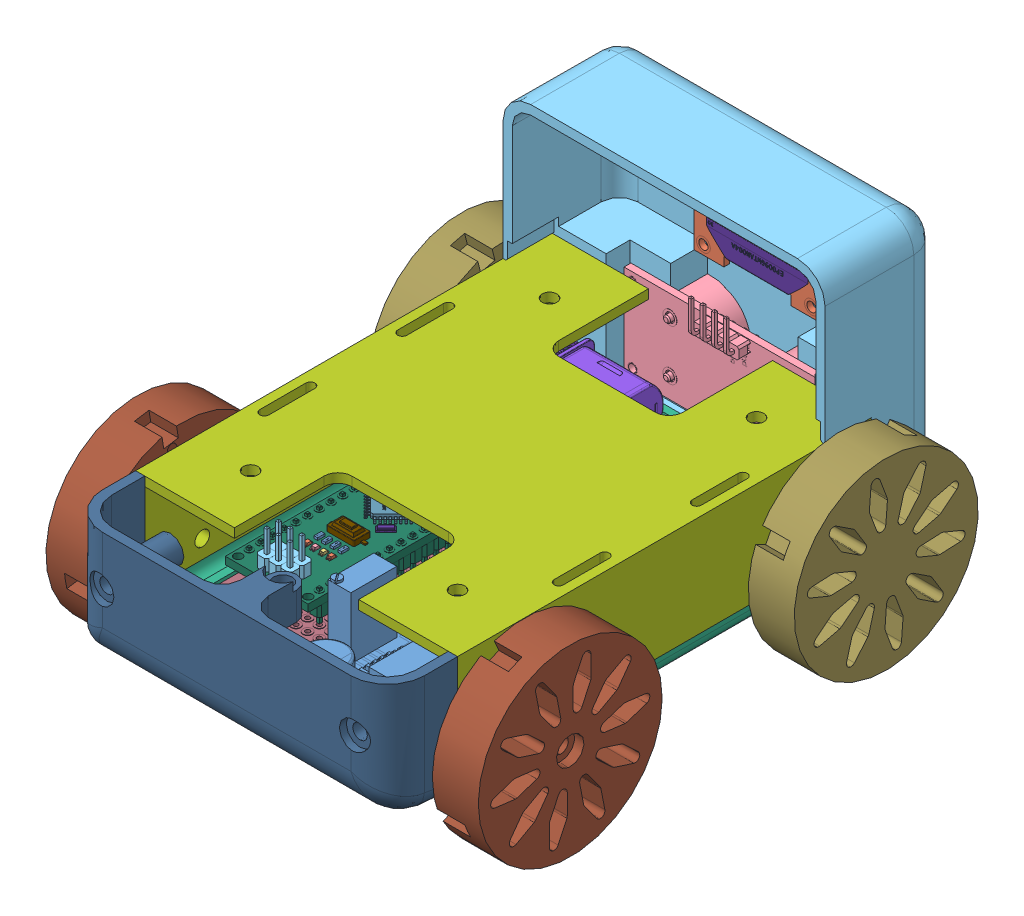
SolidWorks assembly assembling, configuration По умолчанию. Lengths in mm.
Overall size (94 77.03 124.24).
205 component instances, 165 part files, 54 mates.
Components (placement in the parent):
- Weewooday I2C OLED 0.98 128x64.step-2: Weewooday I2C OLED 0.98 128x64.step [По умолчанию] at (61.75 -43.4059 -15.8059) x (-1 0 0) z (0 1 0) size (27.5 4.33 27.8)
  - Weewooday I2C OLED 0.96'' 128x64.step-1: Weewooday I2C OLED 0.96'' 128x64.step [По умолчанию] at origin size (27.5 4.33 27.8)
    - bits.step-1: bits.step [По умолчанию] at origin size (25.27 1.31 10.1)
      - 662k - XC6206P182MR-G_1.step-1: 662k - XC6206P182MR-G_1.step [По умолчанию] at origin size (2.9 1.31 2.79)
      - R SMD 472_1.step-1: R SMD 472_1.step [По умолчанию] at origin size (0.89 0.56 1.7)
      - R SMD 472_2.step-1: R SMD 472_2.step [По умолчанию] at origin size (0.89 0.56 1.7)
      - R SMD 472_3.step-1: R SMD 472_3.step [По умолчанию] at origin size (0.89 0.56 1.7)
      - R SMD 914_1.step-1: R SMD 914_1.step [По умолчанию] at origin size (0.89 0.56 1.7)
      - R SMD 472_4.step-1: R SMD 472_4.step [По умолчанию] at origin size (1.7 0.56 0.89)
      - C SMD 0603_1.step-1: C SMD 0603_1.step [По умолчанию] at origin size (0.8 0.8 1.6)
      - C SMD 0603_2.step-1: C SMD 0603_2.step [По умолчанию] at origin size (0.8 0.8 1.6)
      - C SMD 0603_3.step-1: C SMD 0603_3.step [По умолчанию] at origin size (0.8 0.8 1.6)
      - C SMD 0603_4.step-1: C SMD 0603_4.step [По умолчанию] at origin size (0.8 0.8 1.6)
      - C SMD 0603_5.step-1: C SMD 0603_5.step [По умолчанию] at origin size (0.8 0.8 1.6)
      - C SMD 0603_6.step-1: C SMD 0603_6.step [По умолчанию] at origin size (0.8 0.8 1.6)
      - C SMD 0603_7.step-1: C SMD 0603_7.step [По умолчанию] at origin size (0.8 0.8 1.6)
      - C SMD 0603_8.step-1: C SMD 0603_8.step [По умолчанию] at origin size (0.8 0.8 1.6)
      - SOD323F_DIO_1.step-1: SOD323F_DIO_1.step [По умолчанию] at origin size (0.75 0.82 2.5)
    - flat_cable_1.step-1: flat_cable_1.step [По умолчанию] at origin size (22.01 3.08 9.32)
      - pins.step-1: pins.step [По умолчанию] at origin size (21.2 0.05 3)
      - flat_cable_1-0.step-1: flat_cable_1-0.step [По умолчанию] at origin size (22.01 3.08 7.82)
    - pads.step-1: pads.step [По умолчанию] at origin size (25.48 0.01 10.54)
    - silk screen.step-1: silk screen.step [По умолчанию] at origin size (27.48 1.25 23.58)
    - board_1.step-1: board_1.step [По умолчанию] at origin size (27.5 1.23 27.8)
    - screen_1.step-1: screen_1.step [По умолчанию] at origin size (26.7 1.8 19.26)
- Ultrasonic sensor.step-2: Ultrasonic sensor.step [По умолчанию] at (-26.4481 -23.7121 67.4064) x (-1 0 0) z (0 1 0) size (45 17.8 25.83)
  - ultrasonic sensor.step-1: ultrasonic sensor.step [По умолчанию] at (-40.1981 -57.9064 -18.4379) x (-1 0 0) z (0 -1 0) size (45 25.83 17.8)
- front-bumper-2: front-bumper [По умолчанию] at (13.75 -26.9 -2) x (-1 0 0) z (0 1 0) size (70.34 25.3 58.17)
- bottom-2: bottom [По умолчанию] at (13.75 -55.9 58.2) size (70 10 90)
- User Library-R6_AA_UM3-1_5V_holder4AA(1)-2: User Library-R6_AA_UM3-1_5V_holder4AA(1) [4AA] at (13.75 -14.813 58.2) x (0 0 1) z (0 -1 0) size (59.56 61.47 30.23) (hidden)
- base-2: base [По умолчанию] at (13.75 -51.9 58.2) x (0 0 1) z (0 1 0) size (90 74 22)
- N20 Mini Micro Metall Gear Motor DC 3-6-12V v1-3: N20 Mini Micro Metall Gear Motor DC 3-6-12V v1 [По умолчанию] at (36.95 -47.9 21.2) x (1 0 0) z (0 1 0) size (34.2 12.11 10.34)
- N20 Mini Micro Metall Gear Motor DC 3-6-12V v1-4: N20 Mini Micro Metall Gear Motor DC 3-6-12V v1 [По умолчанию] at (-9.45 -47.9 21.2) x (-1 0 0) z (0 1 0) size (34.2 12.11 10.34)
- 693 ZZ 3-8-4-3: 693 ZZ 3-8-4 [По умолчанию] at (-24.75 -47.9 90.7) x (0 0.003804 0.999993) z (-1 0 0) size (8 8 4)
- 693 ZZ 3-8-4-4: 693 ZZ 3-8-4 [По умолчанию] at (53.25 -47.9 90.7) x (0 0.003804 0.999993) z (-1 0 0) size (8 8 4)
- back-bumper-2: back-bumper [По умолчанию] at (13.75 -29.8 118.4) x (1 0 0) z (0 1 0) size (70.34 15.21 26.17)
- roof-2: roof [По умолчанию] at (13.75 2.1 70.85) x (1 0 0) z (0 0 -1) size (70 34 99.1) (hidden)
- back-wheel-1: back-wheel [По умолчанию] at (-33.25 -47.9 90.7) x (0 -0.987279 -0.158998) z (0 -0.158998 0.987279) size (40 10 40)
- back-wheel-2: back-wheel [По умолчанию] at (60.75 -47.9 90.7) x (0 -0.916751 -0.399458) z (0 0.399458 -0.916751) size (40 10 40)
- front-wheel-1: front-wheel [По умолчанию] at (59.95 -47.9 21.2) x (0 0.883956 -0.46757) z (0 0.46757 0.883956) size (40 10 40)
- front-wheel-2: front-wheel [По умолчанию] at (-32.45 -47.9 21.2) x (0 0.97042 0.241423) z (0 0.241423 -0.97042) size (40 10 40)
- pcb_5x7.step-1: pcb_5x7.step [По умолчанию] at (13.75 -50.3 65.2342) x (0 0 1) z (0 1 0) size (70 50 1.8)
- Arduino Nano.step-1: Arduino Nano.step [По умолчанию] at (-17.2484 -45.3384 50.0291) x (0 0 1) z (0 1 0) size (44.28 18 13.68)
  - ATMEGA328P-AU.STEP.step-1: ATMEGA328P-AU.STEP.step [По умолчанию] at (19.8219 24.4243 4.0882) x (-0.707107 -0.707107 0) z (0 0 1) size (9 9 1.2)
    - ATMEGA328P-AU--3DModel-STEP-56544.step.STEP.STEP.STEP.step-1: ATMEGA328P-AU--3DModel-STEP-56544.step.STEP.STEP.STEP.step [По умолчанию] at (2.8163 4.1 0.6768) x (1 0 0) z (0 -1 0) size (9 1.2 9)
  - Arduino Nano_1.step-1: Arduino Nano_1.step [По умолчанию] at (8.8551 11.9484 0) size (43.18 18 6.8)
  - Mini USB.step-1: Mini USB.step [По умолчанию] at (8.5451 19.5727 4.14) size (9.5 9.7 3.9)
  - CSTCE Crystal.step-1: CSTCE Crystal.step [По умолчанию] at (25.8562 23.1047 4.15) x (0.707107 -0.707107 0) z (0 0 1) size (3.2 1.35 0.71)
  - 2Pin Tactile Switch 6x3.6.step-1: 2Pin Tactile Switch 6x3.6.step [По умолчанию] at (30.7142 19.8184 4.14) x (0 1 0) z (0 0 1) size (7.9 3.6 2.2)
  - 0603 Resistor.step-1: 0603 Resistor.step [По умолчанию] at (34.4251 22.4184 4.14) size (1.6 0.8 0.5)
  - 0603 Resistor.step-2: 0603 Resistor.step [По умолчанию] at (34.4251 20.7184 4.14) size (1.6 0.8 0.5)
  - 0603 Resistor.step-3: 0603 Resistor.step [По умолчанию] at (34.4251 18.9184 4.14) size (1.6 0.8 0.5)
  - 0603 Resistor.step-4: 0603 Resistor.step [По умолчанию] at (34.4251 17.2184 4.14) size (1.6 0.8 0.5)
  - Blue LED.step-1: Blue LED.step [По умолчанию] at (37.0251 22.4184 4.14) size (1.6 0.8 0.6)
  - Green LED.step-1: Green LED.step [По умолчанию] at (37.0251 20.7184 4.14) size (1.6 0.8 0.6)
  - Red LED.step-1: Red LED.step [По умолчанию] at (37.0251 18.9184 4.14) size (1.6 0.8 0.6)
  - Blue LED.step-2: Blue LED.step [По умолчанию] at (37.0251 17.2184 4.14) size (1.6 0.8 0.6)
  - Header 2x3.step-1: Header 2x3.step [По умолчанию] at (45.6765 17.0321 4.14) x (0 1 0) z (0 0 1) size (7.62 5.07 10)
  - SOT89.step-1: SOT89.step [По умолчанию] at (38.4751 17.3184 0.94) x (0 1 0) z (0 0 1) size (6.5 7.1 1.6)
  - 1206 Tantalum.step-1: 1206 Tantalum.step [По умолчанию] at (38.6251 22.3684 2.54) x (-1 0 0) z (0 0 -1) size (3.2 1.6 1.5)
  - 0603 Resistor.step-5: 0603 Resistor.step [По умолчанию] at (38.4251 24.9684 2.54) x (-1 0 0) z (0 0 -1) size (1.6 0.8 0.5)
  - 0603 Capacitor.step-1: 0603 Capacitor.step [По умолчанию] at (35.0338 14.4684 2.54) x (-1 0 0) z (0 0 -1) size (1.6 0.8 0.7)
  - 1206 Tantalum.step-2: 1206 Tantalum.step [По умолчанию] at (7.6451 24.3684 2.54) x (1 0 0) z (0 0 -1) size (3.2 1.6 1.5)
  - 0603 Capacitor.step-2: 0603 Capacitor.step [По умолчанию] at (6.9059 22.4745 2.54) x (-1 0 0) z (0 0 -1) size (1.6 0.8 0.7)
  - 0603 Capacitor.step-3: 0603 Capacitor.step [По умолчанию] at (17.8451 14.0245 2.54) x (-1 0 0) z (0 0 -1) size (1.6 0.8 0.7)
  - 0603 Capacitor.step-4: 0603 Capacitor.step [По умолчанию] at (17.8451 15.0767 2.54) x (-1 0 0) z (0 0 -1) size (1.6 0.8 0.7)
  - 0603 Capacitor.step-5: 0603 Capacitor.step [По умолчанию] at (25.3451 21.2855 2.54) x (-1 0 0) z (0 0 -1) size (1.6 0.8 0.7)
  - 0603 Resistor.step-6: 0603 Resistor.step [По умолчанию] at (23.8451 15.8601 2.54) x (-1 0 0) z (0 0 -1) size (1.6 0.8 0.5)
  - 0603 Resistor.step-7: 0603 Resistor.step [По умолчанию] at (23.8451 14.4709 2.54) x (-1 0 0) z (0 0 -1) size (1.6 0.8 0.5)
  - CSTCE Crystal.step-2: CSTCE Crystal.step [По умолчанию] at (13.1731 14.7184 2.53) x (-1 0 0) z (0 0 -1) size (3.2 1.35 0.71)
  - SOIC16.step-1: SOIC16.step [По умолчанию] at (16.6451 19.5642 2.54) x (-1 0 0) z (0 0 -1) size (10.2 6 1.5)
- Sparkfun Motor Driver.step-1: Sparkfun Motor Driver.step [По умолчанию] at (26.5355 -43.7326 33.0099) x (0 0 -1) z (0 1 0) size (20.9 20.98 11.14)
  - pin6.step-1: pin6.step [По умолчанию] at (-6.347 18.1939 -12.4725) x (1 0 0) z (0 -1 0) size (2.45 11.14 2.54)
  - pin6.step-2: pin6.step [По умолчанию] at (-6.347 15.6539 -12.4725) x (1 0 0) z (0 -1 0) size (2.45 11.14 2.54)
  - pin6.step-3: pin6.step [По умолчанию] at (-6.347 13.1139 -12.4725) x (1 0 0) z (0 -1 0) size (2.45 11.14 2.54)
  - pin6.step-4: pin6.step [По умолчанию] at (-6.347 10.5739 -12.4725) x (1 0 0) z (0 -1 0) size (2.45 11.14 2.54)
  - pin6.step-5: pin6.step [По умолчанию] at (-6.347 8.0339 -12.4725) x (1 0 0) z (0 -1 0) size (2.45 11.14 2.54)
  - pin6.step-6: pin6.step [По умолчанию] at (-6.347 5.4939 -12.4725) x (1 0 0) z (0 -1 0) size (2.45 11.14 2.54)
  - pin6.step-7: pin6.step [По умолчанию] at (-6.347 2.9539 -12.4725) x (1 0 0) z (0 -1 0) size (2.45 11.14 2.54)
  - pin6.step-8: pin6.step [По умолчанию] at (-6.347 0.4139 -12.4725) x (1 0 0) z (0 -1 0) size (2.45 11.14 2.54)
  - pin6.step-9: pin6.step [По умолчанию] at (-21.333 0.4139 -12.4725) x (1 0 0) z (0 -1 0) size (2.45 11.14 2.54)
  - pin6.step-10: pin6.step [По умолчанию] at (-21.333 2.9539 -12.4725) x (1 0 0) z (0 -1 0) size (2.45 11.14 2.54)
  - pin6.step-11: pin6.step [По умолчанию] at (-21.333 5.4939 -12.4725) x (1 0 0) z (0 -1 0) size (2.45 11.14 2.54)
  - pin6.step-12: pin6.step [По умолчанию] at (-21.333 8.0339 -12.4725) x (1 0 0) z (0 -1 0) size (2.45 11.14 2.54)
  - pin6.step-13: pin6.step [По умолчанию] at (-21.333 10.5739 -12.4725) x (1 0 0) z (0 -1 0) size (2.45 11.14 2.54)
  - pin6.step-14: pin6.step [По умолчанию] at (-21.333 13.1139 -12.4725) x (1 0 0) z (0 -1 0) size (2.45 11.14 2.54)
  - pin6.step-15: pin6.step [По умолчанию] at (-21.333 15.6539 -12.4725) x (1 0 0) z (0 -1 0) size (2.45 11.14 2.54)
  - pin6.step-16: pin6.step [По умолчанию] at (-21.333 18.1939 -12.4725) x (1 0 0) z (0 -1 0) size (2.45 11.14 2.54)
  - Motor Driver.step-1: Motor Driver.step [По умолчанию] at origin size (20.9 20.98 1.65)
  - Motor Driver-0.step-1: Motor Driver-0.step [По умолчанию] at origin size (0.63 0.64 0.01)
  - Motor Driver-1.step-1: Motor Driver-1.step [По умолчанию] at origin size (2.01 3.8 0.01)
  - Motor Driver-2.step-1: Motor Driver-2.step [По умолчанию] at origin size (3.81 1.83 0.03)
  - Motor Driver-3.step-1: Motor Driver-3.step [По умолчанию] at origin size (1.81 3.8 0.01)
  - Motor Driver-4.step-1: Motor Driver-4.step [По умолчанию] at origin size (3.81 1.83 0.03)
  - Motor Driver-5.step-1: Motor Driver-5.step [По умолчанию] at origin size (3.81 1.83 0.03)
  - Motor Driver-6.step-1: Motor Driver-6.step [По умолчанию] at origin size (3.81 1.83 0.03)
  - Motor Driver-7.step-1: Motor Driver-7.step [По умолчанию] at origin size (3.81 1.83 0.03)
  - Motor Driver-8.step-1: Motor Driver-8.step [По умолчанию] at origin size (3.81 1.83 0.03)
  - Motor Driver-9.step-1: Motor Driver-9.step [По умолчанию] at origin size (3.81 1.83 0.03)
  - Motor Driver-10.step-1: Motor Driver-10.step [По умолчанию] at origin size (3.81 1.83 0.03)
  - Motor Driver-11.step-1: Motor Driver-11.step [По умолчанию] at origin size (3.81 1.83 0.03)
  - Motor Driver-12.step-1: Motor Driver-12.step [По умолчанию] at origin size (3.81 1.83 0.03)
  - Motor Driver-13.step-1: Motor Driver-13.step [По умолчанию] at origin size (3.81 1.83 0.03)
  - Motor Driver-14.step-1: Motor Driver-14.step [По умолчанию] at origin size (3.81 1.83 0.03)
  - Motor Driver-15.step-1: Motor Driver-15.step [По умолчанию] at origin size (3.81 1.83 0.03)
  - Motor Driver-16.step-1: Motor Driver-16.step [По умолчанию] at origin size (3.81 1.83 0.03)
  - Motor Driver-17.step-1: Motor Driver-17.step [По умолчанию] at origin size (3.81 1.83 0.03)
  - Motor Driver-18.step-1: Motor Driver-18.step [По умолчанию] at origin size (3.81 1.83 0.03)
  - Motor Driver-19.step-1: Motor Driver-19.step [По умолчанию] at origin size (1.8 0.86 0.64)
  - Motor Driver-20.step-1: Motor Driver-20.step [По умолчанию] at origin size (1.8 0.86 0.64)
  - Motor Driver-21.step-1: Motor Driver-21.step [По умолчанию] at origin size (4.17 2.79 1.92)
  - Motor Driver-22.step-1: Motor Driver-22.step [По умолчанию] at origin size (0.63 0.64 0.01)
  - Motor Driver-23.step-1: Motor Driver-23.step [По умолчанию] at origin size (1.27 0.91 0.66)
  - Motor Driver-24.step-1: Motor Driver-24.step [По умолчанию] at origin size (1.27 0.91 0.66)
  - Motor Driver-25.step-1: Motor Driver-25.step [По умолчанию] at origin size (5.03 6.97 1.14)
  - Motor Driver-26.step-1: Motor Driver-26.step [По умолчанию] at origin size (4.37 0.38 0.01)
  - Motor Driver-27.step-1: Motor Driver-27.step [По умолчанию] at origin size (4.37 0.38 0.01)
  - Motor Driver-28.step-1: Motor Driver-28.step [По умолчанию] at origin size (0.65 0.89 0.02)
  - Motor Driver-29.step-1: Motor Driver-29.step [По умолчанию] at origin size (0.84 0.89 0.02)
  - Motor Driver-30.step-1: Motor Driver-30.step [По умолчанию] at origin size (0.65 0.89 0.02)
  - Motor Driver-31.step-1: Motor Driver-31.step [По умолчанию] at origin size (0.73 0.92 0.02)
  - Motor Driver-32.step-1: Motor Driver-32.step [По умолчанию] at origin size (0.76 0.89 0.02)
  - Motor Driver-33.step-1: Motor Driver-33.step [По умолчанию] at origin size (0.52 0.89 0.02)
  - Motor Driver-34.step-1: Motor Driver-34.step [По умолчанию] at origin size (0.65 0.89 0.02)
  - Motor Driver-35.step-1: Motor Driver-35.step [По умолчанию] at origin size (0.66 0.89 0.02)
  - Motor Driver-36.step-1: Motor Driver-36.step [По умолчанию] at origin size (0.73 0.92 0.02)
  - Motor Driver-37.step-1: Motor Driver-37.step [По умолчанию] at origin size (0.39 0.89 0.02)
  - Motor Driver-38.step-1: Motor Driver-38.step [По умолчанию] at origin size (0.65 0.89 0.02)
  - Motor Driver-39.step-1: Motor Driver-39.step [По умолчанию] at origin size (1.49 0.27 0.85)
  - Motor Driver-40.step-1: Motor Driver-40.step [По умолчанию] at origin size (1.49 0.27 0.85)
  - Motor Driver-41.step-1: Motor Driver-41.step [По умолчанию] at origin size (1.49 0.27 0.85)
  - Motor Driver-42.step-1: Motor Driver-42.step [По умолчанию] at origin size (1.49 0.27 0.85)
  - Motor Driver-43.step-1: Motor Driver-43.step [По умолчанию] at origin size (1.49 0.27 0.85)
  - Motor Driver-44.step-1: Motor Driver-44.step [По умолчанию] at origin size (1.49 0.27 0.85)
  - Motor Driver-45.step-1: Motor Driver-45.step [По умолчанию] at origin size (1.49 0.27 0.85)
  - Motor Driver-46.step-1: Motor Driver-46.step [По умолчанию] at origin size (1.49 0.27 0.85)
  - Motor Driver-47.step-1: Motor Driver-47.step [По умолчанию] at origin size (1.49 0.27 0.85)
  - Motor Driver-48.step-1: Motor Driver-48.step [По умолчанию] at origin size (1.49 0.27 0.85)
  - Motor Driver-49.step-1: Motor Driver-49.step [По умолчанию] at origin size (1.49 0.27 0.85)
  - Motor Driver-50.step-1: Motor Driver-50.step [По умолчанию] at origin size (1.49 0.27 0.85)
  - Motor Driver-51.step-1: Motor Driver-51.step [По умолчанию] at origin size (1.49 0.27 0.85)
  - Motor Driver-52.step-1: Motor Driver-52.step [По умолчанию] at origin size (1.49 0.27 0.85)
  - Motor Driver-53.step-1: Motor Driver-53.step [По умолчанию] at origin size (1.49 0.27 0.85)
  - Motor Driver-54.step-1: Motor Driver-54.step [По умолчанию] at origin size (1.49 0.27 0.85)
  - Motor Driver-55.step-1: Motor Driver-55.step [По умолчанию] at origin size (1.49 0.27 0.85)
  - Motor Driver-56.step-1: Motor Driver-56.step [По умолчанию] at origin size (1.49 0.27 0.85)
  - Motor Driver-57.step-1: Motor Driver-57.step [По умолчанию] at origin size (1.49 0.27 0.85)
  - Motor Driver-58.step-1: Motor Driver-58.step [По умолчанию] at origin size (1.49 0.27 0.85)
  - Motor Driver-59.step-1: Motor Driver-59.step [По умолчанию] at origin size (1.49 0.27 0.85)
  - Motor Driver-60.step-1: Motor Driver-60.step [По умолчанию] at origin size (1.49 0.27 0.85)
  - Motor Driver-61.step-1: Motor Driver-61.step [По умолчанию] at origin size (1.49 0.27 0.85)
  - Motor Driver-62.step-1: Motor Driver-62.step [По умолчанию] at origin size (1.49 0.27 0.85)
  - Motor Driver-63.step-1: Motor Driver-63.step [По умолчанию] at origin size (0.58 0.76 0.03)
  - Motor Driver-64.step-1: Motor Driver-64.step [По умолчанию] at origin size (0.53 0.76 0.03)
  - Motor Driver-65.step-1: Motor Driver-65.step [По умолчанию] at origin size (0.45 0.76 0.03)
  - Motor Driver-66.step-1: Motor Driver-66.step [По умолчанию] at origin size (0.33 0.76 0.03)
  - Motor Driver-67.step-1: Motor Driver-67.step [По умолчанию] at origin size (0.51 0.78 0.03)
  - Motor Driver-68.step-1: Motor Driver-68.step [По умолчанию] at origin size (0.53 0.76 0.03)
  - Motor Driver-69.step-1: Motor Driver-69.step [По умолчанию] at origin size (0.56 0.79 0.03)
  - Motor Driver-70.step-1: Motor Driver-70.step [По умолчанию] at origin size (0.58 0.79 0.03)
  - Motor Driver-71.step-1: Motor Driver-71.step [По умолчанию] at origin size (0.58 0.76 0.03)
  - Motor Driver-72.step-1: Motor Driver-72.step [По умолчанию] at origin size (0.65 0.76 0.03)
  - Motor Driver-73.step-1: Motor Driver-73.step [По умолчанию] at origin size (0.54 0.79 0.03)
  - Motor Driver-74.step-1: Motor Driver-74.step [По умолчанию] at origin size (0.72 0.76 0.03)
  - Motor Driver-75.step-1: Motor Driver-75.step [По умолчанию] at origin size (0.66 0.76 0.03)
  - Motor Driver-76.step-1: Motor Driver-76.step [По умолчанию] at origin size (0.72 0.76 0.03)
  - Motor Driver-77.step-1: Motor Driver-77.step [По умолчанию] at origin size (0.66 0.76 0.03)
  - Motor Driver-78.step-1: Motor Driver-78.step [По умолчанию] at origin size (0.45 0.76 0.03)
  - Motor Driver-79.step-1: Motor Driver-79.step [По умолчанию] at origin size (0.33 0.76 0.03)
  - Motor Driver-80.step-1: Motor Driver-80.step [По умолчанию] at origin size (0.53 0.76 0.03)
  - Motor Driver-81.step-1: Motor Driver-81.step [По умолчанию] at origin size (0.66 0.76 0.03)
  - Motor Driver-82.step-1: Motor Driver-82.step [По умолчанию] at origin size (0.56 0.79 0.03)
  - Motor Driver-83.step-1: Motor Driver-83.step [По умолчанию] at origin size (0.51 0.78 0.03)
  - Motor Driver-84.step-1: Motor Driver-84.step [По умолчанию] at origin size (0.53 0.76 0.03)
  - Motor Driver-85.step-1: Motor Driver-85.step [По умолчанию] at origin size (0.9 0.76 0.03)
  - Motor Driver-86.step-1: Motor Driver-86.step [По умолчанию] at origin size (0.56 0.76 0.03)
  - Motor Driver-87.step-1: Motor Driver-87.step [По умолчанию] at origin size (0.58 0.76 0.03)
  - Motor Driver-88.step-1: Motor Driver-88.step [По умолчанию] at origin size (0.58 0.79 0.03)
  - Motor Driver-89.step-1: Motor Driver-89.step [По умолчанию] at origin size (0.72 0.76 0.03)
  - Motor Driver-90.step-1: Motor Driver-90.step [По умолчанию] at origin size (0.52 0.76 0.03)
  - Motor Driver-91.step-1: Motor Driver-91.step [По умолчанию] at origin size (0.56 0.79 0.03)
  - Motor Driver-92.step-1: Motor Driver-92.step [По умолчанию] at origin size (0.66 0.76 0.03)
  - Motor Driver-93.step-1: Motor Driver-93.step [По умолчанию] at origin size (0.51 0.78 0.03)
  - Motor Driver-94.step-1: Motor Driver-94.step [По умолчанию] at origin size (0.45 0.76 0.03)
  - Motor Driver-95.step-1: Motor Driver-95.step [По умолчанию] at origin size (0.56 0.76 0.03)
  - Motor Driver-96.step-1: Motor Driver-96.step [По умолчанию] at origin size (0.66 0.76 0.03)
  - Motor Driver-97.step-1: Motor Driver-97.step [По умолчанию] at origin size (0.33 0.76 0.03)
  - Motor Driver-98.step-1: Motor Driver-98.step [По умолчанию] at origin size (0.51 0.78 0.03)
  - Motor Driver-99.step-1: Motor Driver-99.step [По умолчанию] at origin size (0.9 0.76 0.03)
  - Motor Driver-100.step-1: Motor Driver-100.step [По умолчанию] at origin size (0.52 0.76 0.03)
  - Motor Driver-101.step-1: Motor Driver-101.step [По умолчанию] at origin size (0.65 0.76 0.03)
  - Motor Driver-102.step-1: Motor Driver-102.step [По умолчанию] at origin size (0.54 0.79 0.03)
  - Motor Driver-103.step-1: Motor Driver-103.step [По умолчанию] at origin size (0.56 0.76 0.03)
  - Motor Driver-104.step-1: Motor Driver-104.step [По умолчанию] at origin size (0.58 0.79 0.03)
  - Motor Driver-105.step-1: Motor Driver-105.step [По умолчанию] at origin size (0.62 0.76 0.03)
  - Motor Driver-106.step-1: Motor Driver-106.step [По умолчанию] at origin size (0.45 0.76 0.03)
  - Motor Driver-107.step-1: Motor Driver-107.step [По умолчанию] at origin size (0.33 0.76 0.03)
  - Motor Driver-108.step-1: Motor Driver-108.step [По умолчанию] at origin size (0.53 0.76 0.03)
  - Motor Driver-109.step-1: Motor Driver-109.step [По умолчанию] at origin size (0.53 0.76 0.03)
  - Motor Driver-110.step-1: Motor Driver-110.step [По умолчанию] at origin size (0.56 0.79 0.03)
  - Motor Driver-111.step-1: Motor Driver-111.step [По умолчанию] at origin size (0.56 0.76 0.03)
  - Motor Driver-112.step-1: Motor Driver-112.step [По умолчанию] at origin size (0.58 0.79 0.03)
  - Motor Driver-113.step-1: Motor Driver-113.step [По умолчанию] at origin size (0.63 0.64 0.03)
  - Motor Driver-114.step-1: Motor Driver-114.step [По умолчанию] at origin size (0.63 0.64 0.03)
- Step Down XL4015.step-1: Step Down XL4015.step [По умолчанию] at (27.25 -49.3 88.4) x (1 0 0) z (0 1 0) size (23 54 15.5)
Mates (geometry in assembly coordinates):
- Совпадение1: coincident anti-aligned: plane of Weewooday I2C OLED 0.98 128x64.step-2/Weewooday I2C OLED 0.96'' 128x64.step-1/screen_1.step-1 through (13.75 -15.03 0) normal (0 0 -1)
- Совпадение2: coincident aligned: plane of Weewooday I2C OLED 0.98 128x64.step-2/Weewooday I2C OLED 0.96'' 128x64.step-1/board_1.step-1 through (1.05 0 3.3) normal (0 1 0)
- Совпадение3: coincident anti-aligned: plane of Weewooday I2C OLED 0.98 128x64.step-2/Weewooday I2C OLED 0.96'' 128x64.step-1/board_1.step-1 through (0 -27.8 3.3) normal (-1 0 0)
- Ширина1: width aligned: plane of Weewooday I2C OLED 0.98 128x64.step-2/Weewooday I2C OLED 0.96'' 128x64.step-1/screen_1.step-1 through (1.4 -4.27 0.5) normal (0 1 0); plane of front-bumper-2 through (26.1 -23.53 0.5) normal (0 -1 0); plane of Weewooday I2C OLED 0.98 128x64.step-2/Weewooday I2C OLED 0.96'' 128x64.step-1/screen_1.step-1 through (1.25 -21.9 13.2) normal (0 1 0); plane of front-bumper-2 through (1.25 -5.9 13.2) normal (0 -1 0)
- Совпадение4: coincident anti-aligned: plane of Weewooday I2C OLED 0.98 128x64.step-2/Weewooday I2C OLED 0.96'' 128x64.step-1/screen_1.step-1 through (13.75 -15.03 0) normal (0 0 -1); plane of front-bumper-2 through (13.75 -26.9 0) normal (0 0 1)
- Ширина2: width aligned: plane of front-bumper-2 through (26.25 -5.9 13.2) normal (-1 0 0); plane of Weewooday I2C OLED 0.98 128x64.step-2/Weewooday I2C OLED 0.96'' 128x64.step-1/screen_1.step-1 through (1.25 -5.9 13.2) normal (1 0 0); plane of front-bumper-2 through (0.4 -23.53 0.5) normal (-1 0 0); plane of Weewooday I2C OLED 0.98 128x64.step-2/Weewooday I2C OLED 0.96'' 128x64.step-1/screen_1.step-1 through (27.1 -6.53 0.5) normal (1 0 0)
- Совпадение8: coincident anti-aligned: plane of front-bumper-2 through (13.75 -26.9 13.2) normal (0 0 1); plane of bottom-2 through (48.75 -53.9 13.2) normal (0 0 -1)
- Ширина4: width anti-aligned: plane of bottom-2 through (-21.25 -53.9 13.2) normal (-1 0 0); plane of front-bumper-2 through (48.75 -53.9 13.2) normal (1 0 0); plane of bottom-2 through (48.75 -55.9 0) normal (1 0 0); plane of front-bumper-2 through (-21.25 -55.9 0) normal (-1 0 0)
- Совпадение9: coincident aligned: plane of front-bumper-2 through (-21.25 -55.9 0) normal (0 -1 0); plane of bottom-2 through (13.75 -55.9 58.2) normal (0 -1 0)
- Ширина5: width anti-aligned: plane of User Library-R6_AA_UM3-1_5V_holder4AA(1)-2 through (-16.984 0.3 29.752) normal (-1 0 0); plane of front-bumper-2 through (44.484 0.3 29.752) normal (1 0 0); plane of User Library-R6_AA_UM3-1_5V_holder4AA(1)-2 through (48.75 -55.9 0) normal (1 0 0); plane of front-bumper-2 through (-21.25 -55.9 0) normal (-1 0 0)
- Расстояние1: distance = 0.2 mm anti-aligned: plane of User Library-R6_AA_UM3-1_5V_holder4AA(1)-2 through (44.484 0.3 29.752) normal (0 1 0); plane of front-bumper-2 through (46.75 0.1 119.3065) normal (0 -1 0)
- Ширина7: width anti-aligned: plane of base-2 through (48.75 -29.9 13.2) normal (1 0 0); plane of front-bumper-2 through (-21.25 -29.9 13.2) normal (-1 0 0); plane of base-2 through (-21.25 -55.9 0) normal (-1 0 0); plane of front-bumper-2 through (48.75 -55.9 0) normal (1 0 0)
- Совпадение12: coincident anti-aligned: plane of front-bumper-2 through (13.75 -26.9 13.2) normal (0 0 1); plane of base-2 through (-21.25 -29.9 13.2) normal (0 0 -1)
- Совпадение13: coincident anti-aligned: plane of bottom-2 through (13.75 -51.9 58.2) normal (0 1 0); plane of base-2 through (13.75 -51.9 58.2) normal (0 -1 0)
- Ширина9: width anti-aligned: plane of User Library-R6_AA_UM3-1_5V_holder4AA(1)-2 through (-16.984 0.3 86.648) normal (0 0 1); plane of base-2 through (-16.984 0.3 29.752) normal (0 0 -1); plane of User Library-R6_AA_UM3-1_5V_holder4AA(1)-2 through (-21.25 -29.9 13.2) normal (0 0 -1); plane of base-2 through (-21.25 -29.9 103.2) normal (0 0 1)
- Концентричный1: concentric aligned: cylinder of base-2 through (-21.25 -47.9 21.2) axis (1 0 0) radius 1.9; cylinder of N20 Mini Micro Metall Gear Motor DC 3-6-12V v1-3 through (55.95 -47.9 21.2) axis (1 0 0) radius 1.5
- Совпадение14: coincident anti-aligned: plane of base-2 through (46.75 -29.9 15.2) normal (-1 0 0); plane of N20 Mini Micro Metall Gear Motor DC 3-6-12V v1-3 through (46.75 -52.9 15.2) normal (1 0 0)
- Параллельность1: parallel aligned: plane of base-2 through (13.75 -51.9 58.2) normal (0 -1 0); plane of N20 Mini Micro Metall Gear Motor DC 3-6-12V v1-3 through (45.95 -52.9 27.2) normal (0 -1 0)
- Совпадение16: coincident anti-aligned: plane of base-2 through (-19.25 -29.9 15.2) normal (1 0 0); plane of N20 Mini Micro Metall Gear Motor DC 3-6-12V v1-4 through (-19.25 -52.9 27.2) normal (-1 0 0)
- Концентричный2: concentric anti-aligned: cylinder of base-2 through (-21.25 -47.9 21.2) axis (1 0 0) radius 1.9; cylinder of N20 Mini Micro Metall Gear Motor DC 3-6-12V v1-4 through (-28.45 -47.9 21.2) axis (-1 0 0) radius 1.5
- Параллельность2: parallel aligned: plane of base-2 through (13.75 -51.9 58.2) normal (0 -1 0); plane of N20 Mini Micro Metall Gear Motor DC 3-6-12V v1-4 through (-18.45 -52.9 15.2) normal (0 -1 0)
- Концентричный3: concentric anti-aligned: cylinder of base-2 through (-21.25 -47.9 90.7) axis (1 0 0) radius 1.6; cylinder of 693 ZZ 3-8-4-3 through (-33.64 -47.9 90.7) axis (-1 0 0) radius 1.5
- Совпадение18: coincident anti-aligned: plane of base-2 through (-23.25 -47.9 90.7) normal (-1 0 0); plane of 693 ZZ 3-8-4-3 through (-23.25 -44.05 90.6854) normal (1 0 0)
- Совпадение19: coincident anti-aligned: plane of base-2 through (50.75 -47.9 90.7) normal (1 0 0); plane of 693 ZZ 3-8-4-4 through (50.75 -44.05 90.6854) normal (-1 0 0)
- Концентричный4: concentric aligned: cylinder of base-2 through (-21.25 -47.9 90.7) axis (1 0 0) radius 1.6; cylinder of 693 ZZ 3-8-4-4 through (61.14 -47.9 90.7) axis (1 0 0) radius 1.5
- Совпадение21: coincident anti-aligned: plane of bottom-2 through (48.75 -53.9 103.2) normal (0 0 1); plane of back-bumper-2 through (13.75 -29.8 103.2) normal (0 0 -1)
- Ширина10: width anti-aligned: plane of back-bumper-2 through (-21.25 -55.9 116.4) normal (-1 0 0); plane of base-2 through (48.75 -55.9 116.4) normal (1 0 0); plane of back-bumper-2 through (48.75 -29.9 13.2) normal (1 0 0); plane of base-2 through (-21.25 -29.9 13.2) normal (-1 0 0)
- Совпадение22: coincident aligned: plane of bottom-2 through (13.75 -55.9 58.2) normal (0 -1 0); plane of back-bumper-2 through (48.75 -55.9 116.4) normal (0 -1 0)
- Совпадение23: coincident aligned: plane of front-bumper-2 through (-21.25 2.1 0) normal (0 1 0); plane of roof-2 through (13.75 2.1 70.85) normal (0 1 0)
- Совпадение24: coincident anti-aligned: plane of front-bumper-2 through (13.75 -26.9 23.3) normal (0 0 1); plane of roof-2 through (48.75 0.1 23.3) normal (0 0 -1)
- Ширина11: width anti-aligned: plane of roof-2 through (-21.25 0.1 118.4) normal (-1 0 0); plane of base-2 through (48.75 0.1 118.4) normal (1 0 0); plane of roof-2 through (48.75 -29.9 13.2) normal (1 0 0); plane of base-2 through (-21.25 -29.9 13.2) normal (-1 0 0)
- Ширина12: width anti-aligned: plane of Ultrasonic sensor.step-2/ultrasonic sensor.step-1 through (36.25 -52.15 9.5) normal (1 0 0); plane of Ultrasonic sensor.step-2/ultrasonic sensor.step-1 through (-8.75 -32.15 9.5) normal (-1 0 0); plane of front-bumper-2 through (36.45 -53.9 83.749) normal (-1 0 0); plane of front-bumper-2 through (-8.95 -53.9 83.749) normal (1 0 0)
- Расстояние2: distance = 1.75 mm anti-aligned: plane of Ultrasonic sensor.step-2/ultrasonic sensor.step-1 through (-8.75 -52.15 9.5) normal (0 -1 0); plane of front-bumper-2 through (-19.25 -53.9 119.3065) normal (0 1 0)
- Совпадение26: coincident anti-aligned: plane of Ultrasonic sensor.step-2/ultrasonic sensor.step-1 through (13.75 -42.15 8) normal (0 0 -1); plane of front-bumper-2 through (13.75 -26.9 8) normal (0 0 1)
- Совпадение27: coincident anti-aligned: plane of 693 ZZ 3-8-4-3 through (-27.25 -44.05 90.6854) normal (-1 0 0); plane of back-wheel-1 through (-27.25 -47.9 90.7) normal (1 0 0)
- Совпадение28: coincident anti-aligned: plane of 693 ZZ 3-8-4-4 through (54.75 -44.05 90.6854) normal (1 0 0); plane of back-wheel-2 through (54.75 -47.9 90.7) normal (-1 0 0)
- Концентричный5: concentric aligned: cylinder of 693 ZZ 3-8-4-4 through (61.14 -47.9 90.7) axis (1 0 0) radius 4; cylinder of back-wheel-2 through (50.75 -47.9 90.7) axis (1 0 0) radius 4
- Концентричный6: concentric anti-aligned: cylinder of 693 ZZ 3-8-4-3 through (-16.86 -47.9 90.7) axis (1 0 0) radius 4; cylinder of back-wheel-1 through (-23.25 -47.9 90.7) axis (-1 0 0) radius 4
- Концентричный7: concentric anti-aligned: cylinder of N20 Mini Micro Metall Gear Motor DC 3-6-12V v1-3 through (55.95 -47.9 21.2) axis (1 0 0) radius 1.5; cylinder of front-wheel-1 through (59.95 -47.9 21.2) axis (-1 0 0) radius 1.6
- Концентричный8: concentric anti-aligned: cylinder of N20 Mini Micro Metall Gear Motor DC 3-6-12V v1-4 through (-28.45 -47.9 21.2) axis (-1 0 0) radius 1.5; cylinder of front-wheel-2 through (-32.45 -47.9 21.2) axis (1 0 0) radius 1.6
- Совпадение29: coincident anti-aligned: plane of N20 Mini Micro Metall Gear Motor DC 3-6-12V v1-4 through (-28.45 -49.775 19.325) normal (-1 0 0); plane of front-wheel-2 through (-28.45 -47.9 21.2) normal (1 0 0)
- Совпадение30: coincident anti-aligned: plane of N20 Mini Micro Metall Gear Motor DC 3-6-12V v1-3 through (55.95 -49.775 23.075) normal (1 0 0); plane of front-wheel-1 through (55.95 -47.9 21.2) normal (-1 0 0)
- Ширина13: width anti-aligned: plane of pcb_5x7.step-1 through (-11.25 -50.3 30.2342) normal (-1 0 0); plane of pcb_5x7.step-1 through (38.75 -50.3 100.2342) normal (1 0 0); plane of bottom-2 through (48.75 -53.9 13.2) normal (1 0 0); plane of bottom-2 through (-21.25 -53.9 13.2) normal (-1 0 0)
- Расстояние3: distance = 2 mm anti-aligned: plane of pcb_5x7.step-1 through (13.75 -51.9 65.2342) normal (0 -1 0); plane of bottom-2 through (13.75 -53.9 58.2) normal (0 1 0)
- Концентричный9: concentric anti-aligned: cylinder of pcb_5x7.step-1 through (-5.3 -45.3 94.4442) axis (0 1 0) radius 0.5; cylinder of Arduino Nano.step-1/Arduino Nano_1.step-1 through (-5.3 -41.1384 94.4442) axis (0 -1 0) radius 0.825
- Параллельность3: parallel: line of pcb_5x7.step-1 through (-11.25 -50.3 30.2342) axis (0 0 1); plane of Arduino Nano.step-1/Arduino Nano_1.step-1 through (-6.68 -41.1984 55.0742) normal (-1 0 0)
- Совпадение31: coincident anti-aligned: plane of pcb_5x7.step-1 through (35.34 -50.2 46.1842) normal (0 1 0); plane of Sparkfun Motor Driver.step-1/pin6.step-9 through (35.4763 -50.2 50.9804) normal (0 -1 0)
- Параллельность4: parallel aligned: plane of pcb_5x7.step-1 through (38.75 -50.3 30.2342) normal (0 0 -1); plane of Sparkfun Motor Driver.step-1/Motor Driver.step-1 through (16.0453 -41.1037 33.0353) normal (0 0 -1)
- Совпадение33: coincident: point of Arduino Nano.step-1/ATMEGA328P-AU.STEP.step-1/ATMEGA328P-AU--3DModel-STEP-56544.step.STEP.STEP.STEP.step-1; plane of Sparkfun Motor Driver.step-1/Motor Driver.step-1 through (26.5355 -41.1037 43.4874) normal (0 1 0)
- Параллельность5: parallel anti-aligned: plane of pcb_5x7.step-1 through (13.75 -50.3 65.2342) normal (0 1 0); plane of Step Down XL4015.step-1 through (27.25 -49.3 88.4707) normal (0 -1 0)
- Параллельность6: parallel aligned: plane of Sparkfun Motor Driver.step-1/Motor Driver.step-1 through (37.0257 -41.1037 53.9395) normal (1 0 0); plane of Step Down XL4015.step-1 through (38.75 -47.7 77.8) normal (1 0 0)
- Расстояние4: distance = 1 mm anti-aligned: plane of Step Down XL4015.step-1 through (20.9836 -47.7 115.4) normal (0 0 1); plane of back-bumper-2 through (13.75 -29.8 116.4) normal (0 0 -1)
- Совпадение37: coincident aligned: plane of pcb_5x7.step-1 through (38.75 -50.3 100.2342) normal (1 0 0); plane of Step Down XL4015.step-1 through (38.75 -47.7 77.8) normal (1 0 0)
- Расстояние5: distance = 1 mm anti-aligned: plane of Step Down XL4015.step-1 through (27.25 -49.3 88.4707) normal (0 -1 0); plane of pcb_5x7.step-1 through (13.75 -50.3 65.2342) normal (0 1 0)
